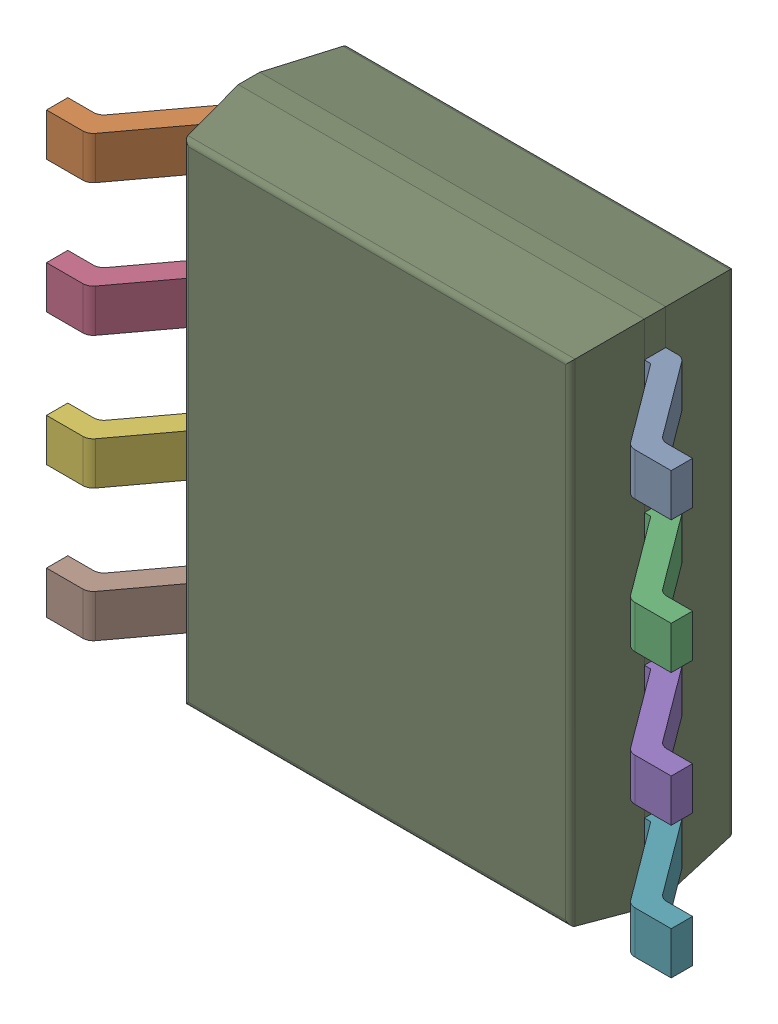
SolidWorks assembly IC2, configuration 默认. Lengths in mm.
Overall size (6 4.9 1.75).
11 component instances, 9 part files, 0 mates.
Components (placement in the parent):
- 6132017696-1: 6132017696 [默认] at (12.491 17.78 -1.6914) x (1 0 0) z (0 0 -1) size (6 4.9 1.75)
  - 6132017696-subassembly-1-1: 6132017696-subassembly-1 [默认] at origin size (6 4.22 1)
    - PinsArrayLR-1: PinsArrayLR [默认] at origin size (1.05 0.41 1)
    - PinsArrayLR-1-1: PinsArrayLR-1 [默认] at origin size (1.05 0.41 1)
    - PinsArrayLR-2-1: PinsArrayLR-2 [默认] at origin size (1.05 0.41 1)
    - PinsArrayLR-3-1: PinsArrayLR-3 [默认] at origin size (1.05 0.41 1)
    - PinsArrayLR-4-1: PinsArrayLR-4 [默认] at origin size (1.05 0.41 1)
    - PinsArrayLR-5-1: PinsArrayLR-5 [默认] at origin size (1.05 0.41 1)
    - PinsArrayLR-6-1: PinsArrayLR-6 [默认] at origin size (1.05 0.41 1)
    - PinsArrayLR-7-1: PinsArrayLR-7 [默认] at origin size (1.05 0.41 1)
  - Body-1: Body [默认] at origin size (3.9 4.9 1.57)
